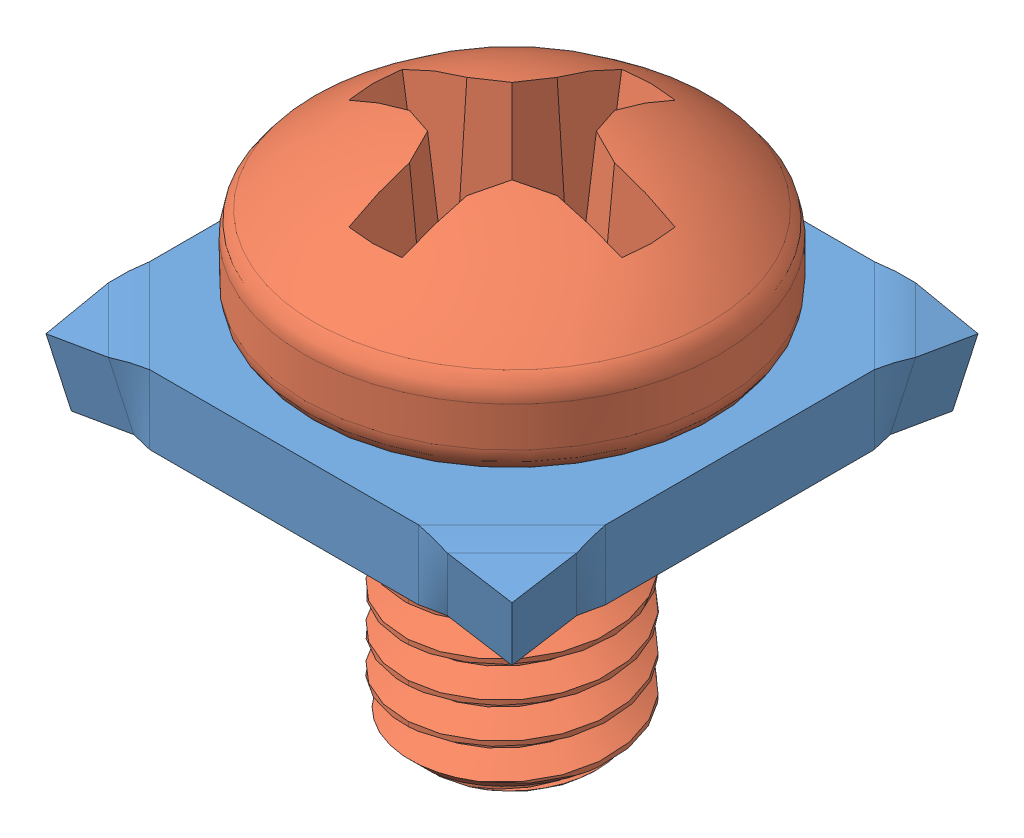
SolidWorks assembly Meanwell_Terminal_Screw, configuration Default. Lengths in mm.
Overall size (8.4 8.8 8.4).
2 component instances, 2 part files, 2 mates.
Components (placement in the parent):
- Clamp Plate Terminal Block-1: Clamp Plate Terminal Block [Default] at origin size (8.4 1.4 8.4)
- Philips-Drive Panhead Screw Terminal Block-1: Philips-Drive Panhead Screw Terminal Block [92000A151] at (0 -6 0) x (1 0 0) z (0 1 0) size (7 7 8.8)
Mates (geometry in assembly coordinates):
- Concentric1: concentric: cylinder of Clamp Plate Terminal Block-1 through (0 0 0) axis (0 1 0) radius 1.85; cylinder of Philips-Drive Panhead Screw Terminal Block-1 through (0 -6 0) axis (0 -1 0) radius 3.5
- Coincident1: coincident anti-aligned: plane of Clamp Plate Terminal Block-1 through (0 0 0) normal (0 1 0); plane of Philips-Drive Panhead Screw Terminal Block-1 through (0 0 0) normal (0 -1 0)
